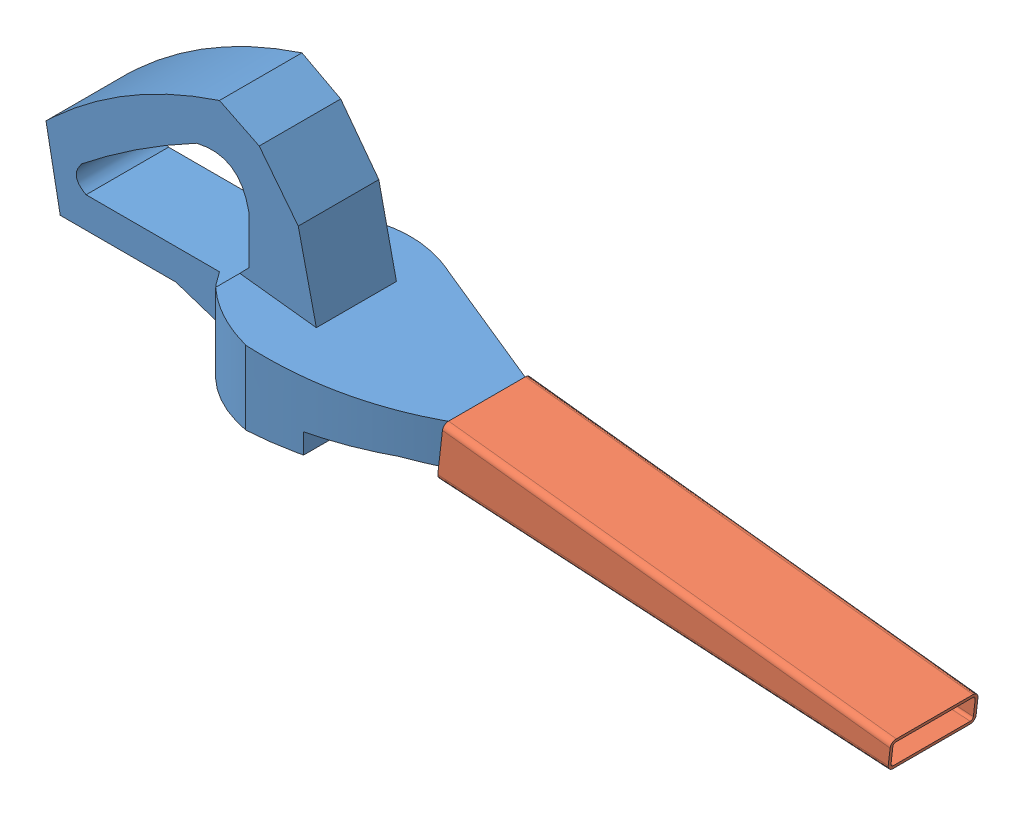
SolidWorks assembly Assem1, configuration Default. Lengths in mm.
Overall size (835.33 242.61 169.13).
2 component instances, 2 part files, 2 mates.
Components (placement in the parent):
- blower-1: blower [Default] at (211.986 78.7515 400.2885) size (835.33 223.79 169.13)
- nozzle-1: nozzle [Default] at (178.078 64.9806 320.83) x (0.993475 -0.11405 0) z (0 0 1) size (410 47.38 80)
Mates (geometry in assembly coordinates):
- Coincident1: coincident: plane of blower-1 through (61.8402 143.7515 231.9604) normal (0.11405 0.993475 0); plane of nozzle-1 through (193.4878 128.6385 320.83) normal (0.11405 0.993475 0)
- Coincident4: coincident aligned: line of blower-1 through (181.8402 129.9756 324.2604) axis (0 0 1); line of nozzle-1 through (181.8402 129.9756 323.9419) axis (0 0 1)
